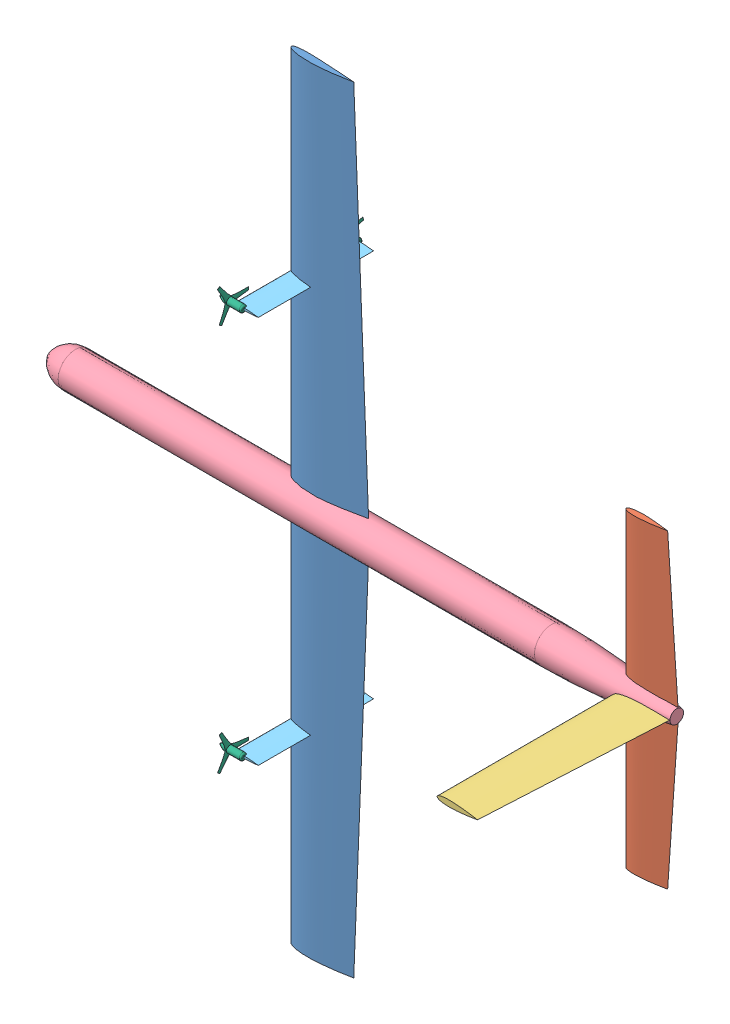
SolidWorks assembly MRkiteAssembly4Turb_FS, configuration Default. Lengths in mm.
Overall size (6470.01 8000.03 2748.92).
10 component instances, 6 part files, 21 mates.
Components (placement in the parent):
- MRwing_FS-1: MRwing_FS [Default] x (1 0 0) z (0 0 -1) size (800.24 8000.03 97.34)
- MRhStab_FS-1: MRhStab_FS [Default] at (3450 0 0) x (1 0 0) z (0 0 -1) size (520.05 3200 79.24)
- MRvStab_FS-1: MRvStab_FS [Default] at (3450 0 0) x (1 0 0) z (0 -1 0) size (520.02 1950.04 78.12)
- MRfuselageWithProp_FS-1: MRfuselageWithProp_FS [Default] at (-2500 0 0) size (6470 355.6 355.6)
- MRturb_FS-1: MRturb_FS [Default] at (0 2000 0) x (1 0 0) z (0 -1 0) size (250 1188 25.14)
- MRturbblade_FS-1: MRturbblade_FS [Default] at (-146.3068 2000 594) x (1 0 0) z (0 -0.451804 -0.892117) size (250 310.36 358.37)
- MRturbblade_FS-2: MRturbblade_FS [Default] at (-146.3068 2000 -594) x (1 0 0) z (0 -0.304641 -0.952467) size (250 310.36 358.37)
- MRturbblade_FS-4: MRturbblade_FS [Default] at (-146.3068 -2000.0001 594.0001) x (1 0 0) z (0 -0.451804 0.892117) size (250 310.36 358.37)
- MRturbblade_FS-5: MRturbblade_FS [Default] at (-146.3068 -2000 -593.9999) x (1 0 0) z (0 -0.304641 0.952467) size (250 310.36 358.37)
- MRturb_FS-2: MRturb_FS [Default] at (0 -2000 0) x (1 0 0) z (0 -1 0) size (250 1188 25.14)
Mates (geometry in assembly coordinates):
- Distance2: distance = 0 mm: plane of assembly through (0 0 0) normal (0 0 1); plane of assembly; plane of MRwing_FS-1 through (0 0 0) normal (0 0 -1)
- Distance3: distance = 0 mm: plane of assembly through (0 0 0) normal (0 1 0); plane of assembly; plane of MRwing_FS-1 through (0 0 0) normal (0 -1 0)
- Distance4: distance = 0 mm: plane of assembly through (0 0 0) normal (1 0 0); plane of assembly; plane of MRwing_FS-1 through (0 0 0) normal (1 0 0)
- Distance5: distance = 0 mm anti-aligned: plane of MRwing_FS-1 through (0 0 0) normal (0 0 -1); plane of MRfuselageWithProp_FS-1 through (-2500 0 0) normal (0 0 1)
- Distance6: distance = 0 mm anti-aligned: plane of MRwing_FS-1 through (0 0 0) normal (0 -1 0); plane of MRfuselageWithProp_FS-1 through (-2500 0 0) normal (0 1 0)
- Distance7: distance = 0 mm aligned: plane of MRhStab_FS-1 through (3450 0 0) normal (0 0 -1); plane of MRwing_FS-1 through (0 0 0) normal (0 0 -1)
- Distance8: distance = 0 mm aligned: plane of MRwing_FS-1 through (0 0 0) normal (0 -1 0); plane of MRhStab_FS-1 through (3450 0 0) normal (0 -1 0)
- Distance10: distance = 0 mm aligned: plane of MRvStab_FS-1 through (3450 0 0) normal (0 -1 0); plane of MRwing_FS-1 through (0 0 0) normal (0 -1 0)
- Distance11: distance = 0 mm anti-aligned: plane of MRwing_FS-1 through (0 0 0) normal (0 0 -1); plane of MRvStab_FS-1 through (3450 0 0) normal (0 0 1)
- Distance14: distance aligned: plane of MRhStab_FS-1 through (3450 0 0) normal (1 0 0); plane of MRwing_FS-1 through (0 0 0) normal (1 0 0)
- Distance15: distance aligned: plane of MRfuselageWithProp_FS-1 through (-2500 0 0) normal (1 0 0); plane of MRwing_FS-1 through (0 0 0) normal (1 0 0)
- Distance16: distance aligned: plane of MRvStab_FS-1 through (3450 0 0) normal (1 0 0); plane of MRwing_FS-1 through (0 0 0) normal (1 0 0)
- Distance17: distance = 0 mm anti-aligned: plane of MRturb_FS-1 through (0 2000 0) normal (0 0 1); plane of MRwing_FS-1 through (0 0 0) normal (0 0 -1)
- Distance18: distance = 2000 mm aligned: plane of MRturb_FS-1 through (0 2000 0) normal (0 -1 0); plane of MRwing_FS-1 through (0 0 0) normal (0 -1 0)
- Distance19: distance = 50 mm aligned: plane of MRturbblade_FS-1 through (-50 2000 594) normal (1 0 0); plane of MRturb_FS-1 through (0 2000 0) normal (1 0 0)
- Coincident2: coincident: plane of MRturb_FS-1 through (0 2000 0) normal (0 -1 0); line of MRturbblade_FS-1 through (81.4952 2000 594) axis (-1 0 0)
- Coincident3: coincident: plane of MRturb_FS-1 through (123.6795 1988.9177 594) normal (0 0 1); line of MRturbblade_FS-1 through (81.4952 2000 594) axis (-1 0 0)
- Coincident4: coincident aligned: plane of MRwing_FS-1 through (0 0 0) normal (1 0 0); plane of MRturb_FS-1 through (0 2000 0) normal (1 0 0)
- Distance20: distance = 50 mm aligned: plane of MRturbblade_FS-2 through (-50 2000 -594) normal (1 0 0); plane of MRturb_FS-1 through (0 2000 0) normal (1 0 0)
- Coincident5: coincident: plane of MRturb_FS-1 through (0 2000 0) normal (0 -1 0); line of MRturbblade_FS-2 through (81.4952 2000 -594) axis (-1 0 0)
- Coincident6: coincident: plane of MRturb_FS-1 through (123.6795 1988.9177 -594) normal (0 0 -1); line of MRturbblade_FS-2 through (81.4952 2000 -594) axis (-1 0 0)
